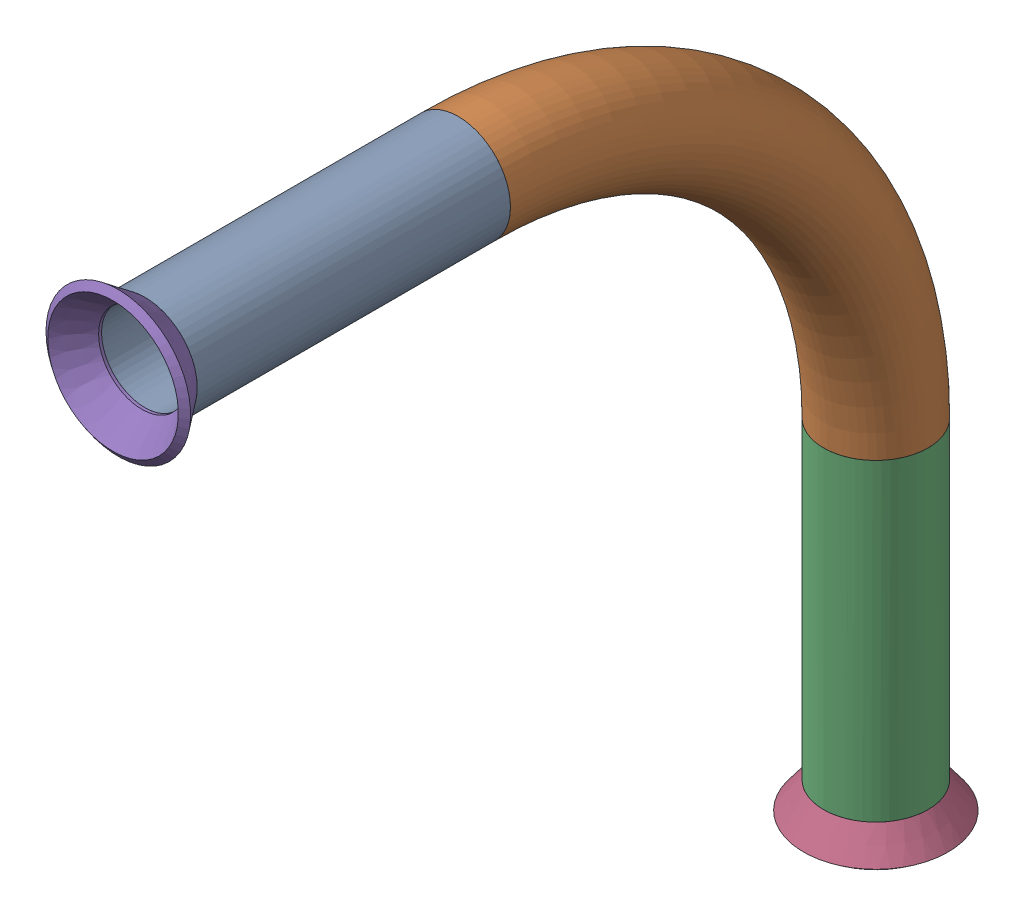
SolidWorks assembly Pipe 8, configuration Default. Lengths in mm.
Overall size (22.99 104.28 101.58).
3 component instances, 2 part files, 0 mates.
Components (placement in the parent):
- part 8-1: part 8 [Default<As Machined>] at origin size (12.7 95.25 95.25)
- Flared pipe end - .5 inch-1: Flared pipe end - .5 inch [Default<As Machined>] at (0 -345.4245 274.6712) x (1 0 0) z (0 -1 0) size (17.59 17.59 3.89)
- Flared pipe end - .5 inch-2: Flared pipe end - .5 inch [Default<As Machined>] at (0 -256.5245 363.5712) x (-0.923728 0.383049 0) z (0 0 1) size (17.59 17.59 3.89)
